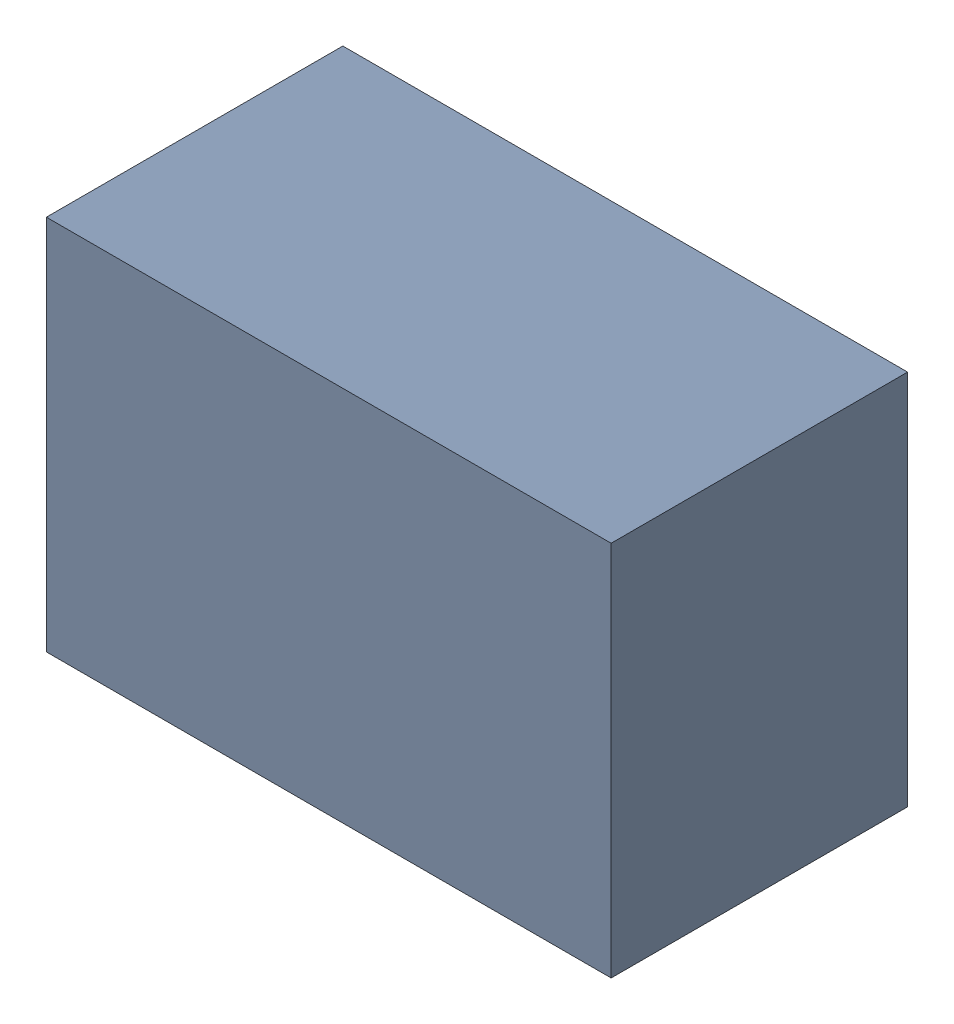
SolidWorks assembly USB01_L1, configuration Default. Lengths in mm.
Overall size (2.29 1.52 1.2).
2 component instances, 1 part files, 0 mates.
Components (placement in the parent):
- 402659088-1: 402659088 [Default] at (158.75 79.375 0) size (2.29 1.52 1.2)
  - Extruded_28-1: Extruded_28 [Default] at origin size (2.29 1.52 1.2)
